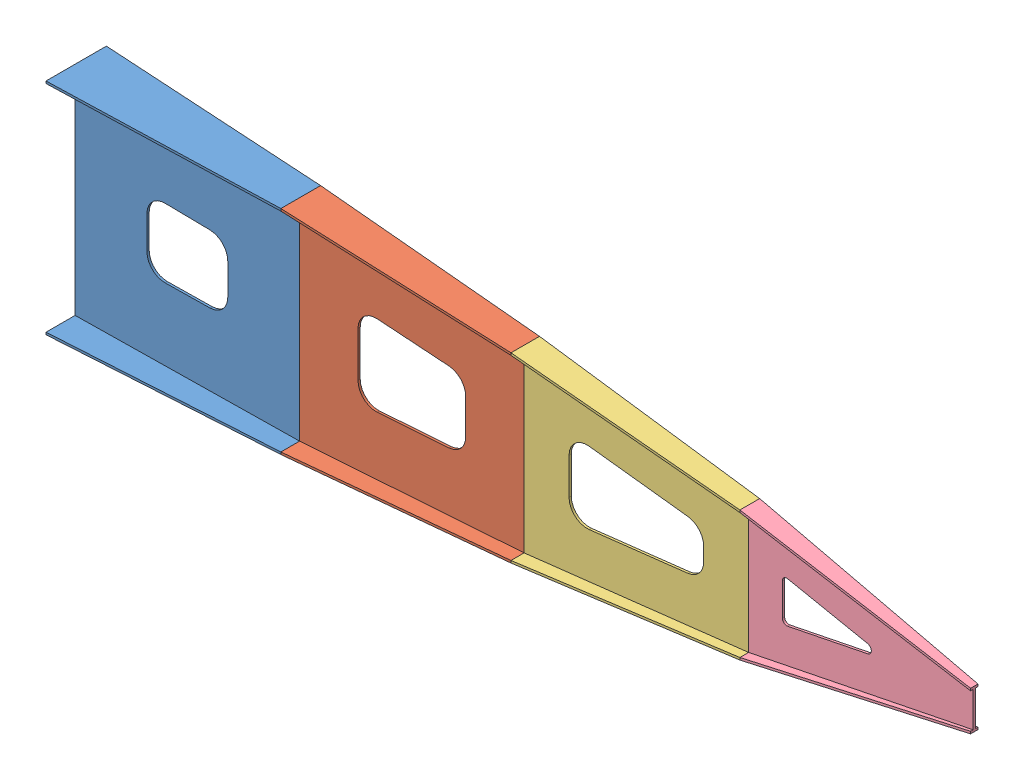
SolidWorks assembly 1.05 tolerance assembly, configuration Default. Lengths in mm.
Overall size (4000 979 269).
4 component instances, 4 part files, 9 mates.
Components (placement in the parent):
- 1-1: 1 [Default] at (-775.9263 612.0858 1043.8579) size (1000 979 269)
- 2-2: 2 [Default] at (224.0737 612.0858 1043.8579) size (1000 949 177)
- 3-2: 3 [Default] at (1224.0737 612.0858 1043.8579) size (1000 811 127)
- 4-2: 4 [Default] at (2224.0737 612.0858 1043.8579) size (1000 579 88)
Mates (geometry in assembly coordinates):
- Coincident39: coincident anti-aligned: plane of 1-1 through (224.0737 612.0858 1043.8579) normal (1 0 0); plane of 2-2 through (224.0737 612.0858 1043.8579) normal (-1 0 0)
- Coincident40: coincident anti-aligned: plane of 2-2 through (1224.0737 612.0858 1043.8579) normal (1 0 0); plane of 3-2 through (1224.0737 612.0858 1043.8579) normal (-1 0 0)
- Coincident42: coincident: point of 1-1; point of 2-2
- Coincident43: coincident: point of 1-1; point of 2-2
- Coincident44: coincident: point of 2-2; point of 3-2
- Coincident46: coincident: point of 2-2; point of 3-2
- Coincident49: coincident: point of 3-2; point of 4-2
- Coincident52: coincident aligned: plane of 3-2 through (1224.0737 612.0858 1053.8579) normal (0 0 1); plane of 4-2 through (2224.0737 612.0858 1053.8579) normal (0 0 1)
- Coincident53: coincident: point of 3-2; point of 4-2
